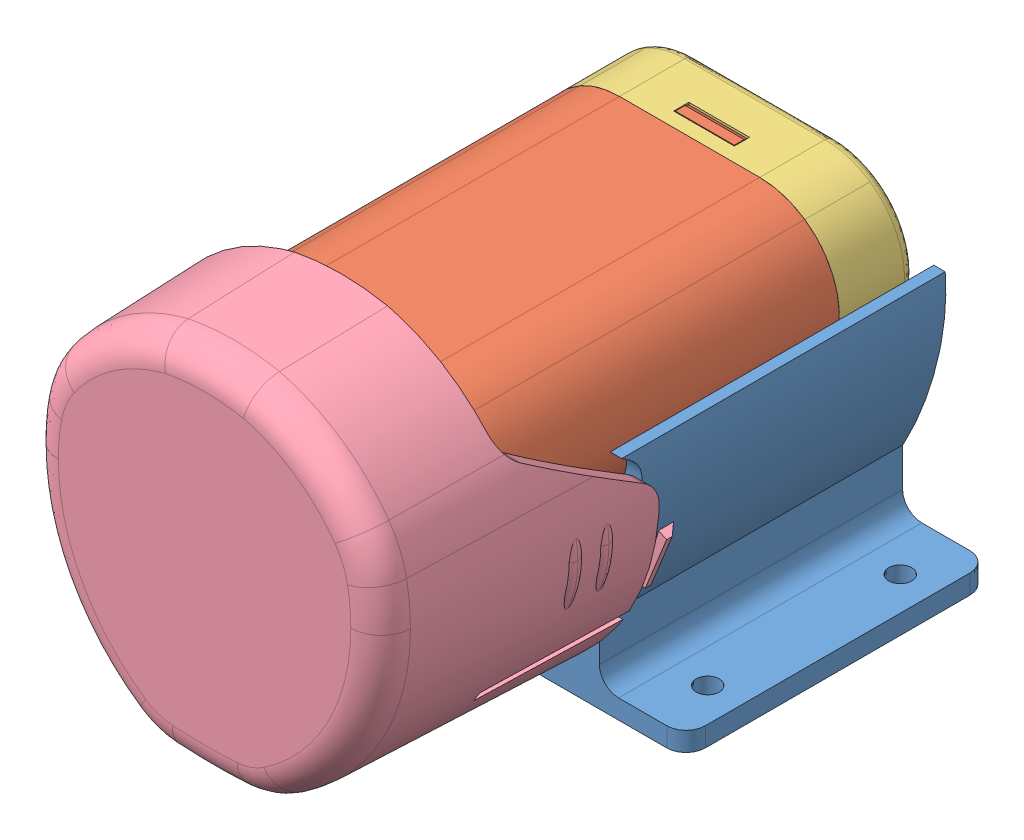
SolidWorks assembly Battery Assembly, configuration Default. Lengths in mm.
Overall size (55.88 50.31 82.98).
6 component instances, 4 part files, 1 mates.
Components (placement in the parent):
- Battery Mount-1: Battery Mount [Default] at (9.0036 39.57 13.1732) size (55.88 33 42.7)
- Battery-1: Battery [Default] at (10.6815 38.6044 113.7732) x (-1 0.000001 0) z (0 0 -1) size (51.94 49.97 82.98)
  - battery.stp-1: battery.stp [Default] at origin size (51.94 49.97 82.98)
    - BOSCH_BATTERY_108_BODY.stp-1: BOSCH_BATTERY_108_BODY.stp [Default] at (1.6476 0.6188 12.9785) x (1 -0.000001 0) z (0 0 1) size (39.5 37.7 66)
    - BOSCH_BATTERY_108_TOP.stp-1: BOSCH_BATTERY_108_TOP.stp [Default] at (1.6476 0.6188 73.9785) x (1 -0.000001 0) z (0 0 1) size (39.5 37.02 19)
    - BOSCH_BATTERY_108_CAP2.stp-1: BOSCH_BATTERY_108_CAP2.stp [Default] at (1.6476 -0.3955 10) x (1 -0.000001 0) z (0 0 1) size (51.94 49.97 42.78)
Mates (geometry in assembly coordinates):
- Lock1: lock: unknown of Battery Mount-1; unknown of Battery-1/battery.stp-1/BOSCH_BATTERY_108_TOP.stp-1
